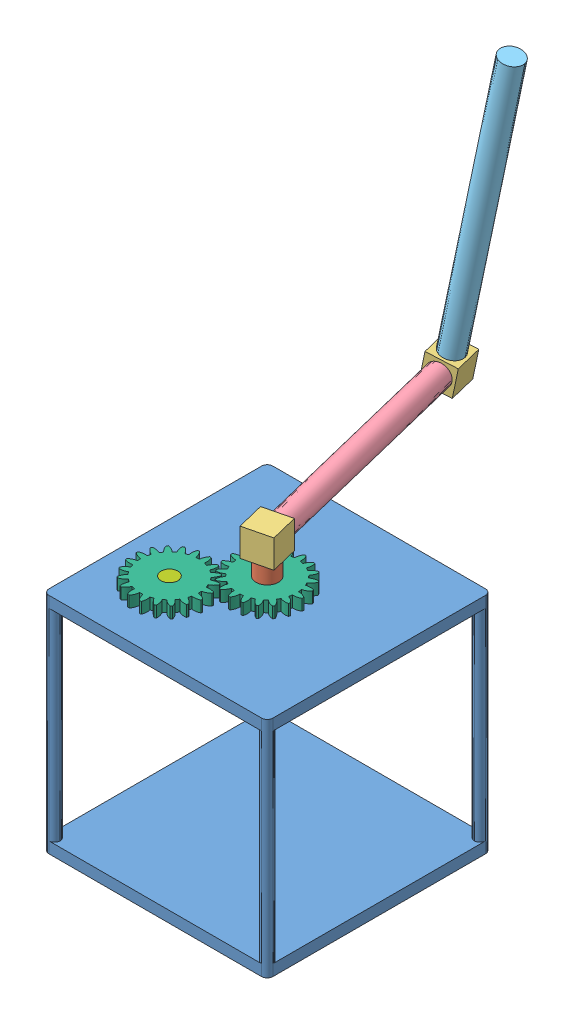
SolidWorks assembly Assem4 with mate gear, configuration Default. Lengths in mm.
Overall size (400 999.49 680.59).
11 component instances, 7 part files, 26 mates.
Components (placement in the parent):
- body-1: body [Default] at (152.1901 30.957 290.4214) size (400 400 400)
- mile1-1: mile1 [Default] at (152.1901 410.957 290.4214) x (-0.467007 0 -0.884254) z (0.884254 0 -0.467007) size (40 80 40)
- conector1-1: conector1 [Default] at (152.1901 488.957 290.4214) x (0.971111 0 -0.238629) z (0.238629 0 0.971111) size (50 50 50)
- mile2-2: mile2 [Default] at (147.4175 513.957 270.9992) x (-0.000758 1 0.000186) z (-0.97111 -0.00078 0.238629) size (40 400 40)
- conector1-2: conector1 [Default] at (52.4432 513.957 -115.5029) x (-0.955493 0.178623 0.234791) z (-0.173463 -0.983918 0.042625) size (50 50 50)
- mile3-1: mile3 [Default] at (49.9467 533.6353 -140.6331) x (0.723055 -0.15662 -0.672801) z (0.668657 -0.085886 0.738595) size (40 500 40)
- spur gear_iso-1: spur gear_iso [ISO - Spur gear 6M 20T 20PA 20FW ---S20A75H50L40.0N] at (152.1901 455.957 290.4214) x (0 -1 0) z (0.684393 0 0.729113) size (20 130.83 130.83)
- spur gear_iso-2: spur gear_iso [ISO - Spur gear 6M 20T 20PA 20FW ---S20A75H50L30.0N] at (64.8624 455.957 377.7491) x (0 -1 0) z (0.785929 0 -0.618317) size (20 130.83 130.83)
- mile_motor-1: mile_motor [Default] at (64.8624 395.957 377.7491) x (0.838034 0 -0.545618) z (0.545618 0 0.838034) size (30 60 30)
- conector1-3: conector1 [Default] at (64.8624 397.957 377.7491) x (-0.474896 0 -0.880042) z (-0.880042 0 0.474896) size (50 50 50)
- mile1-2: mile1 [Default] at (152.8666 372.957 330.2595) x (-0.211607 0.895239 -0.392134) z (0.425145 0.445585 0.787848) size (40 80 40)
Mates (geometry in assembly coordinates):
- Concentric1: concentric: cylinder of body-1 through (152.1901 410.957 290.4214) axis (0 1 0) radius 20; cylinder of mile1-1 through (152.1901 490.957 290.4214) axis (0 -1 0) radius 20
- Concentric4: concentric: cylinder of mile1-1 through (152.1901 490.957 290.4214) axis (0 -1 0) radius 20; cylinder of conector1-1 through (152.1901 490.957 290.4214) axis (0 -1 0) radius 20
- Coincident3: coincident: plane of mile1-1 through (152.1901 490.957 290.4214) normal (0 1 0); plane of conector1-1 through (152.1901 490.957 290.4214) normal (0 -1 0)
- Concentric7: concentric: cylinder of conector1-1 through (147.4175 513.957 270.9992) axis (-0.238629 0 -0.971111) radius 20; cylinder of mile2-2 through (51.9659 513.957 -117.4451) axis (0.238629 0 0.971111) radius 20
- Concentric8: concentric: cylinder of conector1-1 through (147.4175 513.957 270.9992) axis (-0.238629 0 -0.971111) radius 20; cylinder of mile2-2 through (51.9659 513.957 -117.4451) axis (0.238629 0 0.971111) radius 20
- Coincident4: coincident: plane of conector1-1 through (147.4175 513.957 270.9992) normal (-0.238629 0 -0.971111); plane of mile2-2 through (147.4175 513.957 270.9992) normal (0.238629 0 0.971111)
- Concentric10: concentric: circle of mile2-2; circle of conector1-2
- Concentric11: concentric: circle of mile2-2; circle of conector1-2
- Coincident8: coincident: plane of mile2-2 through (51.9659 513.957 -117.4451) normal (-0.238629 0 -0.971111); plane of conector1-2 through (51.9659 513.957 -117.4451) normal (0.238629 0 0.971111)
- Concentric12: concentric: cylinder of conector1-2 through (49.9467 533.6353 -140.6331) axis (0.173463 0.983918 -0.042625) radius 20; cylinder of mile3-1 through (136.678 1025.5941 -161.9454) axis (-0.173463 -0.983918 0.042625) radius 20
- Coincident9: coincident: plane of conector1-2 through (49.9467 533.6353 -140.6331) normal (0.173463 0.983918 -0.042625); plane of mile3-1 through (49.9467 533.6353 -140.6331) normal (-0.173463 -0.983918 0.042625)
- Concentric13: concentric: cylinder of mile1-1 through (152.1901 490.957 290.4214) axis (0 -1 0) radius 20; cylinder of spur gear_iso-1 through (152.1901 405.9569 290.4214) axis (0 1 0) radius 20
- Coincident10: coincident: plane of spur gear_iso-1 through (152.1901 455.957 290.4214) normal (0 1 0); plane of spur gear_iso-2 through (64.8624 455.957 377.7491) normal (0 1 0)
- Concentric15: concentric: cylinder of body-1 through (64.8624 359.957 377.7491) axis (0 1 0) radius 15; cylinder of spur gear_iso-2 through (64.8624 405.9569 377.7491) axis (0 1 0) radius 15
- Concentric17: concentric: cylinder of mile1-1 through (152.1901 490.957 290.4214) axis (0 -1 0) radius 20; cylinder of spur gear_iso-1 through (152.1901 405.9569 290.4214) axis (0 1 0) radius 20
- Coincident12: coincident: plane of body-1 through (332.1901 410.957 90.4214) normal (0 -1 0); plane of mile1-1 through (152.1901 410.957 290.4214) normal (0 -1 0)
- Concentric18: concentric: cylinder of spur gear_iso-2 through (64.8624 405.9569 377.7491) axis (0 1 0) radius 15; cylinder of mile_motor-1 through (64.8624 455.957 377.7491) axis (0 -1 0) radius 15
- Concentric19: concentric: cylinder of spur gear_iso-2 through (64.8624 405.9569 377.7491) axis (0 1 0) radius 15; cylinder of mile_motor-1 through (64.8624 455.957 377.7491) axis (0 -1 0) radius 15
- Coincident14: coincident: plane of spur gear_iso-2 through (64.8624 455.957 377.7491) normal (0 1 0); plane of mile_motor-1 through (64.8624 455.957 377.7491) normal (0 1 0)
- Distance1: distance = 15 mm: plane of body-1 through (332.1901 410.957 90.4214) normal (0 -1 0); plane of mile_motor-1 through (64.8624 395.957 377.7491) normal (0 -1 0)
- Concentric20: concentric: cylinder of mile_motor-1 through (64.8624 455.957 377.7491) axis (0 -1 0) radius 15; cylinder of conector1-3 through (64.8624 395.957 377.7491) axis (0 1 0) radius 20
- Concentric21: concentric: cylinder of mile_motor-1 through (64.8624 455.957 377.7491) axis (0 -1 0) radius 15; cylinder of conector1-3 through (64.8624 395.957 377.7491) axis (0 1 0) radius 20
- Coincident16: coincident: plane of conector1-3 through (82.4633 372.957 368.2512) normal (0.880042 0 -0.474896); plane of mile1-2 through (82.4633 372.957 368.2512) normal (-0.880042 0 0.474896)
- Concentric22: concentric: cylinder of conector1-3 through (82.4633 372.957 368.2512) axis (0.880042 0 -0.474896) radius 20; cylinder of mile1-2 through (82.4633 372.957 368.2512) axis (0.880042 0 -0.474896) radius 20
- Coincident17: coincident: plane of mile_motor-1 through (64.8624 395.957 377.7491) normal (0 -1 0); plane of conector1-3 through (64.8624 395.957 377.7491) normal (0 1 0)
- GearMate4: gear = 40 : 40 mm: cylinder of spur gear_iso-1 through (152.1901 405.9569 290.4214) axis (0 1 0) radius 20; cylinder of spur gear_iso-2 through (64.8624 405.9569 377.7491) axis (0 1 0) radius 15
